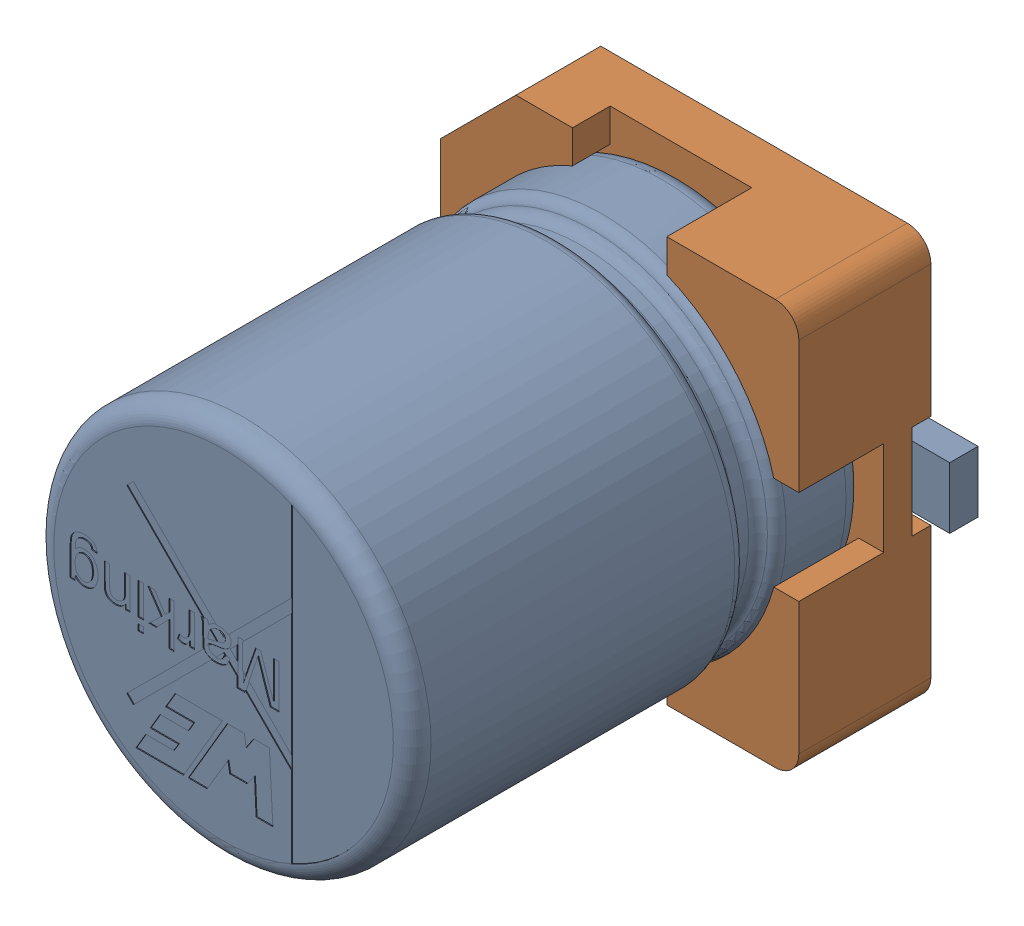
SolidWorks assembly C11, configuration Default. Lengths in mm.
Overall size (5 4.3 5.5).
3 component instances, 2 part files, 0 mates.
Components (placement in the parent):
- 4x5.5x1-1: 4x5.5x1 [Default] at (46.3805 29.3878 0.1) x (0 -1 0) z (0 0 1) size (4.3 5 5.5)
  - capicitor_4x5.5x1-1: capicitor_4x5.5x1 [Default] at (0 0 0.5) x (0 -1 0) z (0 0 1) size (5 4 5.5)
  - Base___X2__03A6__X0__4Capacitor-1: Base___X2__03A6__X0__4Capacitor [Default] at origin size (4.3 4.3 1.46)
